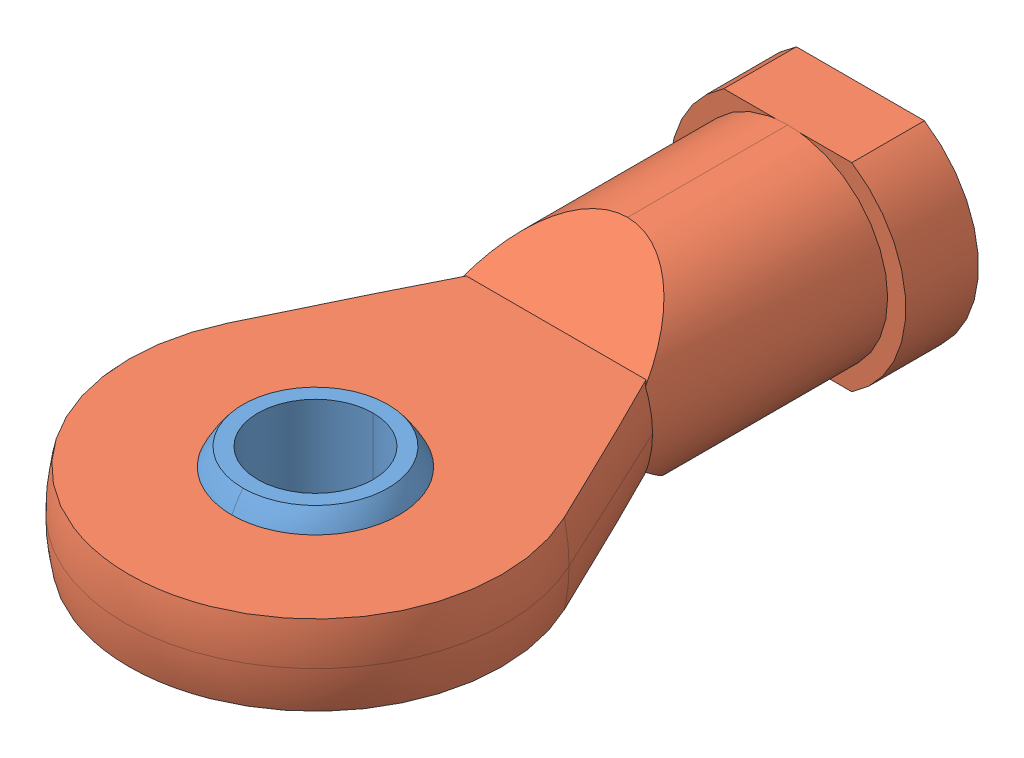
SolidWorks assembly GE-20364, configuration Default. Lengths in mm.
Overall size (21.01 11 40.5).
3 component instances, 2 part files, 0 mates.
Components (placement in the parent):
- EBRI_04_1.stp-1: EBRI_04_1.stp [Default] at (17.252 20.7561 39.9686) size (21.01 11 40.5)
  - 2019_09_04__15-44-22-530.stp-1: 2019_09_04__15-44-22-530.stp [Default] at origin size (10.2 6.35 10.2)
  - 2019_09_04__15-44-22-530-0.stp-1: 2019_09_04__15-44-22-530-0.stp [Default] at origin size (21.01 11 40.5)
